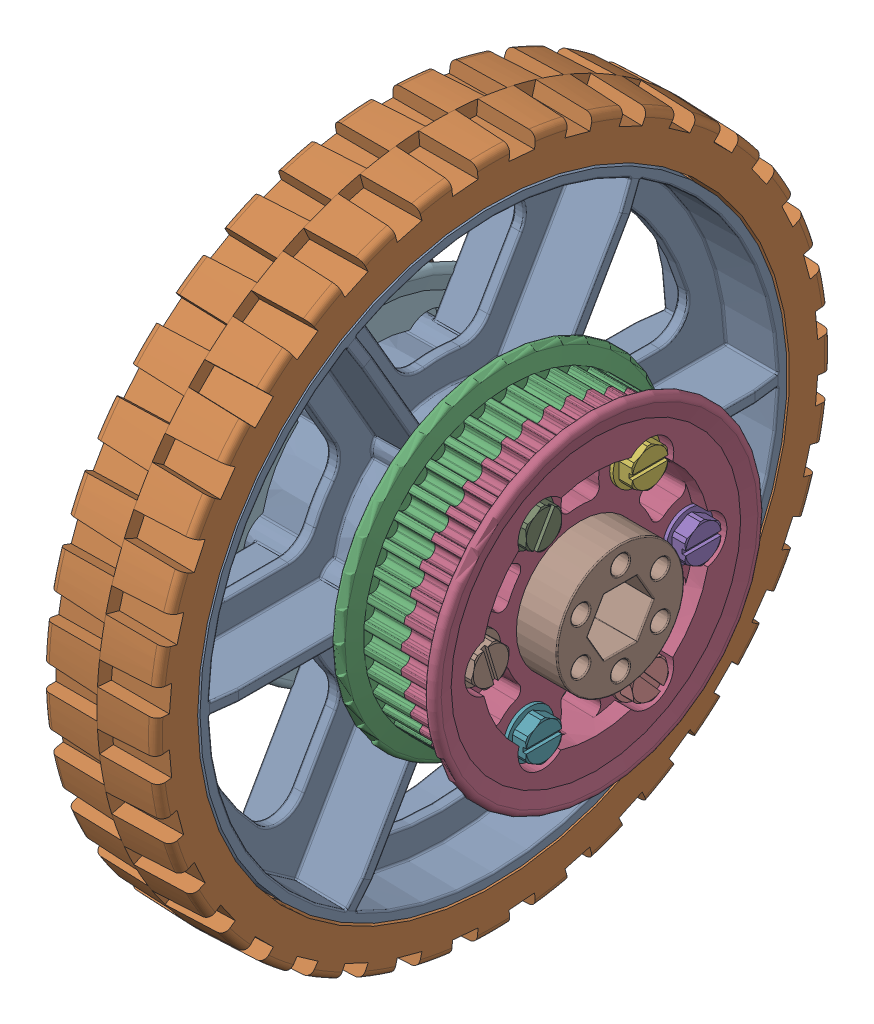
SolidWorks assembly 6 HiGrip with hub and double pulley, configuration Default. Lengths in mm.
Overall size (81.42 152.4 152.4).
21 component instances, 6 part files, 0 mates.
Components (placement in the parent):
- 6 HiGrip Asm Rev II-1: 6 HiGrip Asm Rev II [Default] at (83.7987 67.439 110.9939) size (34.93 152.4 152.4)
  - 6 wheel Rev 4-1: 6 wheel Rev 4 [Default] at (-52.6446 9.4231 21.378) size (34.93 132.08 132.08)
  - 6 wheel tread II-1: 6 wheel tread II [Default] at (-65.3446 9.4231 21.378) x (0 0 -1) z (1 0 0) size (152.4 152.4 25.58)
- 42 tooth HTD Pulley half 2014-1: 42 tooth HTD Pulley half 2014 [Default] at (47.6006 76.862 132.3719) x (1 0 0) z (0 -0.5 0.866025) size (13 74.23 74.23)
- 42 tooth HTD Pulley half 2014-2: 42 tooth HTD Pulley half 2014 [Default] at (64.263 76.862 132.3719) x (-1 0 0) z (0 -0.499927 0.866067) size (13 74.23 74.23)
- 10-24 Hex Washer Rolling x 1.25_93882A213-1: 10-24 Hex Washer Rolling x 1.25_93882A213 [Default] at (63.247 76.8605 108.5602) x (0 0 -1) z (1 0 0) size (10.52 10.52 35.59)
- 10-24 Hex Washer Rolling x 1.25_93882A213-2: 10-24 Hex Washer Rolling x 1.25_93882A213 [Default] at (63.247 97.4833 120.4656) x (0 0 -1) z (1 0 0) size (10.52 10.52 35.59)
- 10-24 Hex Washer Rolling x 1.25_93882A213-3: 10-24 Hex Washer Rolling x 1.25_93882A213 [Default] at (63.247 56.2398 144.2799) x (0 0 -1) z (1 0 0) size (10.52 10.52 35.59)
- 10-24 Hex Washer Rolling x 1.25_93882A213-4: 10-24 Hex Washer Rolling x 1.25_93882A213 [Default] at (63.247 76.8625 156.1852) x (0 -0.95788 -0.287168) z (1 0 0) size (10.52 10.52 35.59)
- 10-24 Hex Washer Rolling x 1.25_93882A213-5: 10-24 Hex Washer Rolling x 1.25_93882A213 [Default] at (63.247 97.4843 144.2781) x (0 -0.868976 0.494854) z (1 0 0) size (10.52 10.52 35.59)
- 10-24 Hex Washer Rolling x 1.25_93882A213-6: 10-24 Hex Washer Rolling x 1.25_93882A213 [Default] at (63.247 56.2388 120.4674) x (0 -0.748729 -0.662876) z (1 0 0) size (10.52 10.52 35.59)
- 42 tooth HTD Pulley half 2014-3: 42 tooth HTD Pulley half 2014 [Default] at (-1.9548 76.8628 132.3714) x (1 0 0) z (0 -1 -0.000063) size (13 74.23 74.23)
- 42 tooth HTD Pulley half 2014-4: 42 tooth HTD Pulley half 2014 [Default] at (14.7076 76.8628 132.3714) x (-1 0 0) z (0 -1 0.000021) size (13 74.23 74.23)
- 500EX Hex Hub-1: 500EX Hex Hub [Default] at (-8.3048 76.8628 132.3714) x (0 -0.866025 -0.5) z (0 -0.5 0.866025) size (55.37 25.4 51.33)
- 10-24 Hex Washer Rolling x 1.25_93882A213-7: 10-24 Hex Washer Rolling x 1.25_93882A213 [Default] at (-5.2568 97.485 120.4652) x (0 0 1) z (-1 0 0) size (10.52 10.52 35.59)
- 10-24 Hex Washer Rolling x 1.25_93882A213-8: 10-24 Hex Washer Rolling x 1.25_93882A213 [Default] at (-5.2568 76.8628 108.5589) x (0 0 1) z (-1 0 0) size (10.52 10.52 35.59)
- 10-24 Hex Washer Rolling x 1.25_93882A213-9: 10-24 Hex Washer Rolling x 1.25_93882A213 [Default] at (-5.2568 56.2406 120.4652) x (0 0 1) z (-1 0 0) size (10.52 10.52 35.59)
- 10-24 Hex Washer Rolling x 1.25_93882A213-10: 10-24 Hex Washer Rolling x 1.25_93882A213 [Default] at (-5.2568 97.485 144.2777) x (0 -0.99374 -0.111715) z (-1 0 0) size (10.52 10.52 35.59)
- 10-24 Hex Washer Rolling x 1.25_93882A213-11: 10-24 Hex Washer Rolling x 1.25_93882A213 [Default] at (-5.2568 56.2406 144.2777) x (0 -0.138911 0.990305) z (-1 0 0) size (10.52 10.52 35.59)
- 10-24 Hex Washer Rolling x 1.25_93882A213-12: 10-24 Hex Washer Rolling x 1.25_93882A213 [Default] at (-5.2568 76.8628 156.1839) x (0 -0.98811 -0.15375) z (-1 0 0) size (10.52 10.52 35.59)
- am-1305 500 Hex Spacer-1: am-1305 500 Hex Spacer [Default] at (57.8495 76.862 132.3719) x (0 -0.866025 -0.5) z (0 -0.5 0.866025) size (28.55 14.48 28.55)
